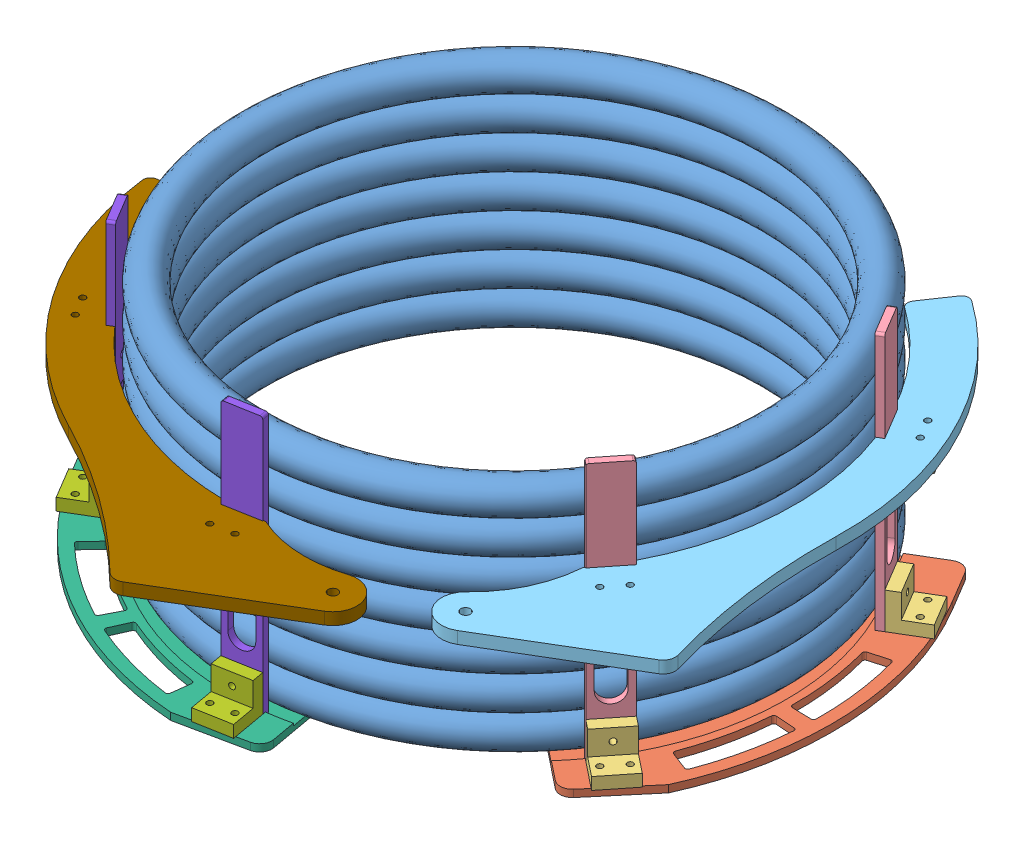
SolidWorks assembly A加环夹爪, configuration 默认. Lengths in mm.
Overall size (338.54 110 313.47).
19 component instances, 9 part files, 11 mates.
Components (placement in the parent):
- 多环-1: 多环 [默认] at (-7.4138 -26.5236 230) size (230 98 230)
- A夹爪装配-1: A夹爪装配 [默认] at (36.2322 -9.6809 36.9173) x (0.858465 0 -0.512872) z (0.512872 0 0.858465) size (126.9 110 201.45)
  - 三层板-1-1: 三层板-1 [默认] at (-137.9953 -25.8427 145.6868) size (101.33 3 140.33)
  - 单孔角码-3: 单孔角码 [默认] at (-13.4953 -7.8427 150.6868) x (0 0 1) z (1 0 0) size (15 15 15)
  - 单孔角码-4: 单孔角码 [默认] at (-71.7706 -7.8427 250.4147) x (-0.935646 0 0.352941) z (0.352941 0 0.935646) size (15 15 15)
  - 固定板-1: 固定板 [默认] at (-21.4953 -25.8427 165.6868) x (0 0 -1) z (0 -1 0) size (15 3 110)
  - 固定板-2: 固定板 [默认] at (-73.5353 -25.8427 245.7365) x (-0.935646 0 0.352941) z (0 -1 0) size (15 3 110)
  - 三层板-2-1: 三层板-2 [默认] at (-134.4953 41.6573 145.6868) size (126.9 5 201.45)
  - 单孔角码-5: 单孔角码 [默认] at (-13.4953 26.6573 165.6868) x (0 0 -1) z (1 0 0) size (15 15 15)
  - 单孔角码-6: 单孔角码 [默认] at (-85.8053 26.6573 255.7089) x (0.935646 0 -0.352941) z (0.352941 0 0.935646) size (15 15 15)
- 镜向A夹爪装配-1: 镜向A夹爪装配 [默认] at (-198.1207 -9.6809 176.9266) x (-0.858465 0 0.512872) z (-0.512872 0 -0.858465) size (126.9 110 201.45)
  - 镜向三层板-1-1: 镜向三层板-1 [默认] at (-137.9953 -25.8427 -145.6868) size (101.33 3 140.33)
  - 镜向单孔角码-1: 镜向单孔角码 [默认] at (-13.4953 -7.8427 -150.6868) x (0 0 -1) z (-1 0 0) size (15 15 15)
  - 镜向单孔角码-2: 镜向单孔角码 [默认] at (-71.7706 -7.8427 -250.4147) x (-0.935646 0 -0.352941) z (-0.352941 0 0.935646) size (15 15 15)
  - 镜向固定板-1: 镜向固定板 [默认] at (-21.4953 -25.8427 -165.6868) x (0 0 1) z (0 1 0) size (15 3 110)
  - 镜向固定板-2: 镜向固定板 [默认] at (-73.5353 -25.8427 -245.7365) x (-0.935646 0 -0.352941) z (0 1 0) size (15 3 110)
  - 镜向三层板-2-1: 镜向三层板-2 [默认] at (-134.4953 41.6573 -145.6868) size (126.9 5 201.45)
  - 镜向单孔角码-3: 镜向单孔角码 [默认] at (-13.4953 26.6573 -165.6868) x (0 0 1) z (-1 0 0) size (15 15 15)
  - 镜向单孔角码-4: 镜向单孔角码 [默认] at (-85.8053 26.6573 -255.7089) x (0.935646 0 0.352941) z (-0.352941 0 0.935646) size (15 15 15)
Mates (geometry in assembly coordinates):
- 相切1: tangent anti-aligned: torus of 多环-1; plane of A夹爪装配-1/固定板-1 through (102.7553 -35.5236 190.1779) normal (-0.858465 0 0.512872)
- 相切4: tangent anti-aligned: torus of 多环-1; plane of A夹爪装配-1/固定板-2 through (96.7875 -35.5236 283.7211) normal (-0.782854 0 -0.622205)
- 相切5: tangent anti-aligned: torus of 多环-1; plane of A夹爪装配-1/固定板-2 through (96.7875 -35.5236 283.7211) normal (-0.782854 0 -0.622205)
- 相切6: tangent anti-aligned: torus of 多环-1; plane of A夹爪装配-1/固定板-1 through (102.7553 -35.5236 190.1779) normal (-0.858465 0 0.512872)
- 相切7: tangent anti-aligned: torus of 多环-1; plane of A夹爪装配-1/三层板-1-1 through (1.7425 -33.5236 233.3748) normal (0 1 0)
- 相切8: tangent anti-aligned: torus of 多环-1; plane of 镜向A夹爪装配-1/镜向固定板-2 through (-9.4924 -35.5236 347.2158) normal (-0.176879 0 -0.984233)
- 相切11: tangent anti-aligned: torus of 多环-1; plane of 镜向A夹爪装配-1/镜向固定板-1 through (-94.6916 -35.5236 308.1386) normal (0.858465 0 -0.512872)
- 相切12: tangent anti-aligned: torus of 多环-1; plane of 镜向A夹爪装配-1/镜向固定板-1 through (-94.6916 -35.5236 308.1386) normal (0.858465 0 -0.512872)
- 相切13: tangent anti-aligned: torus of 多环-1; plane of 镜向A夹爪装配-1/镜向固定板-2 through (-9.4924 -35.5236 347.2158) normal (-0.176879 0 -0.984233)
- 相切16: tangent anti-aligned: torus of 多环-1; plane of 镜向A夹爪装配-1/镜向三层板-1-1 through (-8.7815 -33.5236 239.6622) normal (0 1 0)
- 重合1: coincident anti-aligned: line of A夹爪装配-1/三层板-2-1 through (85.5983 36.9764 346.5019) axis (0.858465 0 -0.512872); line of 镜向A夹爪装配-1/镜向三层板-2-1 through (51.093 36.9764 367.1163) axis (-0.858465 0 0.512872)
